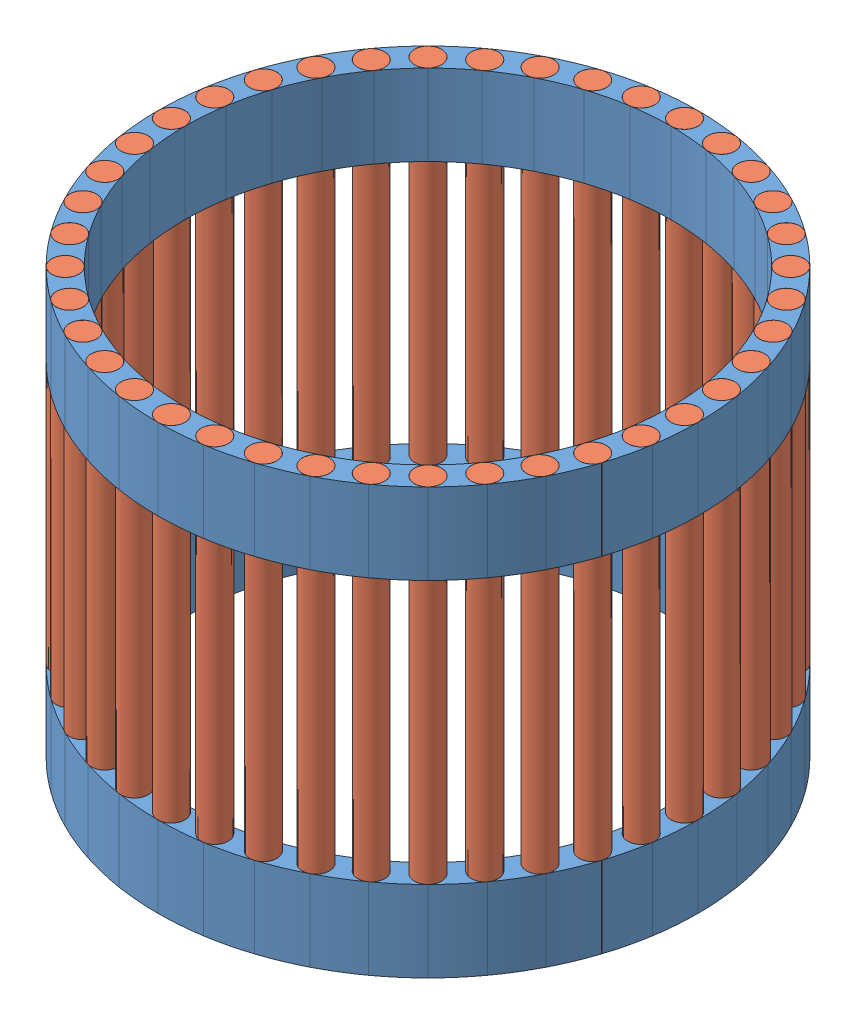
SolidWorks assembly Free Design Assembly, configuration Default. Lengths in mm.
Overall size (290.61 200.03 290.61).
42 component instances, 2 part files, 87 mates.
Components (placement in the parent):
- Free Design-1: Free Design [Default] at origin size (254 38.1 254)
- SchweykZeyn Light Sculpture Rods-1: SchweykZeyn Light Sculpture Rods [7.875 inch] at (-85.3124 0 85.3124) size (12.7 200.03 12.7)
- SchweykZeyn Light Sculpture Rods-15: SchweykZeyn Light Sculpture Rods [7.875 inch] at (-70.9163 0 97.6079) x (0.982082 0 -0.188455) z (0.188455 0 0.982082) size (12.7 200.03 12.7)
- SchweykZeyn Light Sculpture Rods-16: SchweykZeyn Light Sculpture Rods [7.875 inch] at (-54.774 0 107.4999) x (0.918365 0 -0.395734) z (0.395734 0 0.918365) size (12.7 200.03 12.7)
- SchweykZeyn Light Sculpture Rods-17: SchweykZeyn Light Sculpture Rods [7.875 inch] at (-37.2829 0 114.745) x (0.8 0 -0.6) z (0.6 0 0.8) size (12.7 200.03 12.7)
- SchweykZeyn Light Sculpture Rods-18: SchweykZeyn Light Sculpture Rods [7.875 inch] at (-18.8738 0 119.1646) x (0.63358 0 -0.773678) z (0.773678 0 0.63358) size (12.7 200.03 12.7)
- SchweykZeyn Light Sculpture Rods-19: SchweykZeyn Light Sculpture Rods [7.875 inch] at (0 0 120.65) x (0.443629 0 -0.896211) z (0.896211 0 0.443629) size (12.7 200.03 12.7)
- SchweykZeyn Light Sculpture Rods-20: SchweykZeyn Light Sculpture Rods [7.875 inch] at (18.8738 0 119.1646) x (0.263225 0 -0.964735) z (0.964735 0 0.263225) size (12.7 200.03 12.7)
- SchweykZeyn Light Sculpture Rods-21: SchweykZeyn Light Sculpture Rods [7.875 inch] at (37.2829 0 114.745) x (0.120178 0 -0.992752) z (0.992752 0 0.120178) size (12.7 200.03 12.7)
- SchweykZeyn Light Sculpture Rods-23: SchweykZeyn Light Sculpture Rods [7.875 inch] at (-107.4999 0 54.774) x (0 0 -1) z (1 0 0) size (12.7 200.03 12.7)
- SchweykZeyn Light Sculpture Rods-24: SchweykZeyn Light Sculpture Rods [7.875 inch] at (-114.745 0 37.2829) x (0.030377 0 -0.999538) z (0.999538 0 0.030377) size (12.7 200.03 12.7)
- SchweykZeyn Light Sculpture Rods-25: SchweykZeyn Light Sculpture Rods [7.875 inch] at (-119.1646 0 18.8738) x (0.120178 0 -0.992752) z (0.992752 0 0.120178) size (12.7 200.03 12.7)
- SchweykZeyn Light Sculpture Rods-26: SchweykZeyn Light Sculpture Rods [7.875 inch] at (-120.65 0 0) x (0.263225 0 -0.964735) z (0.964735 0 0.263225) size (12.7 200.03 12.7)
- SchweykZeyn Light Sculpture Rods-27: SchweykZeyn Light Sculpture Rods [7.875 inch] at (-119.1646 0 -18.8738) x (0.443629 0 -0.896211) z (0.896211 0 0.443629) size (12.7 200.03 12.7)
- SchweykZeyn Light Sculpture Rods-28: SchweykZeyn Light Sculpture Rods [7.875 inch] at (-114.745 0 -37.2829) x (0.63358 0 -0.773678) z (0.773678 0 0.63358) size (12.7 200.03 12.7)
- SchweykZeyn Light Sculpture Rods-29: SchweykZeyn Light Sculpture Rods [7.875 inch] at (-107.4999 0 -54.774) x (0.8 0 -0.6) z (0.6 0 0.8) size (12.7 200.03 12.7)
- SchweykZeyn Light Sculpture Rods-30: SchweykZeyn Light Sculpture Rods [7.875 inch] at (-97.6079 0 -70.9163) x (0.918365 0 -0.395734) z (0.395734 0 0.918365) size (12.7 200.03 12.7)
- SchweykZeyn Light Sculpture Rods-31: SchweykZeyn Light Sculpture Rods [7.875 inch] at (-85.3124 0 -85.3124) x (0.982082 0 -0.188455) z (0.188455 0 0.982082) size (12.7 200.03 12.7)
- SchweykZeyn Light Sculpture Rods-32: SchweykZeyn Light Sculpture Rods [7.875 inch] at (-70.9163 0 -97.6079) size (12.7 200.03 12.7)
- SchweykZeyn Light Sculpture Rods-33: SchweykZeyn Light Sculpture Rods [7.875 inch] at (-54.774 0 -107.4999) x (0.987317 0 0.158763) z (-0.158763 0 0.987317) size (12.7 200.03 12.7)
- SchweykZeyn Light Sculpture Rods-34: SchweykZeyn Light Sculpture Rods [7.875 inch] at (-37.2829 0 -114.745) x (0.958237 0 0.285974) z (-0.285974 0 0.958237) size (12.7 200.03 12.7)
- SchweykZeyn Light Sculpture Rods-35: SchweykZeyn Light Sculpture Rods [7.875 inch] at (-18.8738 0 -119.1646) x (0.923077 0 0.384615) z (-0.384615 0 0.923077) size (12.7 200.03 12.7)
- SchweykZeyn Light Sculpture Rods-36: SchweykZeyn Light Sculpture Rods [7.875 inch] at (0 0 -120.65) x (0.888293 0 0.459277) z (-0.459277 0 0.888293) size (12.7 200.03 12.7)
- SchweykZeyn Light Sculpture Rods-37: SchweykZeyn Light Sculpture Rods [7.875 inch] at (18.8738 0 -119.1646) x (0.857529 0 0.514435) z (-0.514435 0 0.857529) size (12.7 200.03 12.7)
- SchweykZeyn Light Sculpture Rods-38: SchweykZeyn Light Sculpture Rods [7.875 inch] at (37.2829 0 -114.745) x (0.832666 0 0.553776) z (-0.553776 0 0.832666) size (12.7 200.03 12.7)
- SchweykZeyn Light Sculpture Rods-39: SchweykZeyn Light Sculpture Rods [7.875 inch] at (54.774 0 -107.4999) x (0.814585 0 0.580044) z (-0.580044 0 0.814585) size (12.7 200.03 12.7)
- SchweykZeyn Light Sculpture Rods-40: SchweykZeyn Light Sculpture Rods [7.875 inch] at (70.9163 0 -97.6079) x (0.803653 0 0.595098) z (-0.595098 0 0.803653) size (12.7 200.03 12.7)
- SchweykZeyn Light Sculpture Rods-41: SchweykZeyn Light Sculpture Rods [7.875 inch] at (85.3124 0 -85.3124) x (-0.546944 0 0.837169) z (-0.837169 0 -0.546944) size (12.7 200.03 12.7)
- SchweykZeyn Light Sculpture Rods-42: SchweykZeyn Light Sculpture Rods [7.875 inch] at (97.6079 0 -70.9163) x (0.803653 0 0.595098) z (-0.595098 0 0.803653) size (12.7 200.03 12.7)
- SchweykZeyn Light Sculpture Rods-43: SchweykZeyn Light Sculpture Rods [7.875 inch] at (107.4999 0 -54.774) x (0.814585 0 0.580044) z (-0.580044 0 0.814585) size (12.7 200.03 12.7)
- SchweykZeyn Light Sculpture Rods-44: SchweykZeyn Light Sculpture Rods [7.875 inch] at (114.745 0 -37.2829) x (0.832666 0 0.553776) z (-0.553776 0 0.832666) size (12.7 200.03 12.7)
- SchweykZeyn Light Sculpture Rods-45: SchweykZeyn Light Sculpture Rods [7.875 inch] at (119.1646 0 -18.8738) x (0.857529 0 0.514435) z (-0.514435 0 0.857529) size (12.7 200.03 12.7)
- SchweykZeyn Light Sculpture Rods-46: SchweykZeyn Light Sculpture Rods [7.875 inch] at (120.65 0 0) x (0.888293 0 0.459277) z (-0.459277 0 0.888293) size (12.7 200.03 12.7)
- SchweykZeyn Light Sculpture Rods-47: SchweykZeyn Light Sculpture Rods [7.875 inch] at (119.1646 0 18.8738) x (0.923077 0 0.384615) z (-0.384615 0 0.923077) size (12.7 200.03 12.7)
- SchweykZeyn Light Sculpture Rods-48: SchweykZeyn Light Sculpture Rods [7.875 inch] at (114.745 0 37.2829) x (0.958237 0 0.285974) z (-0.285974 0 0.958237) size (12.7 200.03 12.7)
- SchweykZeyn Light Sculpture Rods-49: SchweykZeyn Light Sculpture Rods [7.875 inch] at (107.4999 0 54.774) x (0.987317 0 0.158763) z (-0.158763 0 0.987317) size (12.7 200.03 12.7)
- SchweykZeyn Light Sculpture Rods-50: SchweykZeyn Light Sculpture Rods [7.875 inch] at (97.6079 0 70.9163) size (12.7 200.03 12.7)
- SchweykZeyn Light Sculpture Rods-51: SchweykZeyn Light Sculpture Rods [7.875 inch] at (85.3124 0 85.3124) x (0.982082 0 -0.188455) z (0.188455 0 0.982082) size (12.7 200.03 12.7)
- SchweykZeyn Light Sculpture Rods-52: SchweykZeyn Light Sculpture Rods [7.875 inch] at (70.9163 0 97.6079) x (0.918365 0 -0.395734) z (0.395734 0 0.918365) size (12.7 200.03 12.7)
- SchweykZeyn Light Sculpture Rods-53: SchweykZeyn Light Sculpture Rods [7.875 inch] at (54.774 0 107.4999) x (0.8 0 -0.6) z (0.6 0 0.8) size (12.7 200.03 12.7)
- SchweykZeyn Light Sculpture Rods-60: SchweykZeyn Light Sculpture Rods [7.875 inch] at (-97.6079 0 70.9163) x (0.982082 0 -0.188455) z (0.188455 0 0.982082) size (12.7 200.03 12.7)
- Free Design-2: Free Design [Default] at (0 161.925 0) x (-0.987688 0 0.156434) z (-0.156434 0 -0.987688) size (254 38.1 254)
Mates (geometry in assembly coordinates):
- Coincident16: coincident aligned: plane of Free Design-1 through (0 0 0) normal (0 -1 0); plane of SchweykZeyn Light Sculpture Rods-1 through (-85.3124 0 85.3124) normal (0 -1 0)
- Concentric5: concentric aligned: cylinder of SchweykZeyn Light Sculpture Rods-1 through (-85.3124 200.025 85.3124) axis (0 -1 0) radius 6.35; cylinder of Free Design-1 through (-85.3124 38.1 85.3124) axis (0 -1 0) radius 6.35
- Concentric6: concentric aligned: cylinder of SchweykZeyn Light Sculpture Rods-1 through (-85.3124 200.025 85.3124) axis (0 -1 0) radius 6.35; cylinder of Free Design-1 through (-85.3124 38.1 85.3124) axis (0 -1 0) radius 6.35
- Coincident17: coincident aligned: plane of Free Design-1 through (0 0 0) normal (0 -1 0); plane of SchweykZeyn Light Sculpture Rods-15 through (-70.9163 0 97.6079) normal (0 -1 0)
- Concentric7: concentric aligned: cylinder of Free Design-1 through (-70.9163 38.1 97.6079) axis (0 -1 0) radius 6.35; cylinder of SchweykZeyn Light Sculpture Rods-15 through (-70.9163 200.025 97.6079) axis (0 -1 0) radius 6.35
- Coincident18: coincident aligned: plane of Free Design-1 through (0 0 0) normal (0 -1 0); plane of SchweykZeyn Light Sculpture Rods-16 through (-54.774 0 107.4999) normal (0 -1 0)
- Concentric8: concentric aligned: cylinder of Free Design-1 through (-54.774 38.1 107.4999) axis (0 -1 0) radius 6.35; cylinder of SchweykZeyn Light Sculpture Rods-16 through (-54.774 200.025 107.4999) axis (0 -1 0) radius 6.35
- Coincident19: coincident aligned: plane of Free Design-1 through (0 0 0) normal (0 -1 0); plane of SchweykZeyn Light Sculpture Rods-17 through (-37.2829 0 114.745) normal (0 -1 0)
- Concentric9: concentric aligned: cylinder of Free Design-1 through (-37.2829 38.1 114.745) axis (0 -1 0) radius 6.35; cylinder of SchweykZeyn Light Sculpture Rods-17 through (-37.2829 200.025 114.745) axis (0 -1 0) radius 6.35
- Coincident20: coincident aligned: plane of Free Design-1 through (0 0 0) normal (0 -1 0); plane of SchweykZeyn Light Sculpture Rods-18 through (-18.8738 0 119.1646) normal (0 -1 0)
- Concentric10: concentric aligned: cylinder of Free Design-1 through (-18.8738 38.1 119.1646) axis (0 -1 0) radius 6.35; cylinder of SchweykZeyn Light Sculpture Rods-18 through (-18.8738 200.025 119.1646) axis (0 -1 0) radius 6.35
- Coincident21: coincident aligned: plane of Free Design-1 through (0 0 0) normal (0 -1 0); plane of SchweykZeyn Light Sculpture Rods-19 through (0 0 120.65) normal (0 -1 0)
- Concentric11: concentric aligned: cylinder of Free Design-1 through (0 38.1 120.65) axis (0 -1 0) radius 6.35; cylinder of SchweykZeyn Light Sculpture Rods-19 through (0 200.025 120.65) axis (0 -1 0) radius 6.35
- Coincident22: coincident aligned: plane of Free Design-1 through (0 0 0) normal (0 -1 0); plane of SchweykZeyn Light Sculpture Rods-20 through (18.8738 0 119.1646) normal (0 -1 0)
- Concentric12: concentric aligned: cylinder of Free Design-1 through (18.8738 38.1 119.1646) axis (0 -1 0) radius 6.35; cylinder of SchweykZeyn Light Sculpture Rods-20 through (18.8738 200.025 119.1646) axis (0 -1 0) radius 6.35
- Coincident23: coincident aligned: plane of Free Design-1 through (0 0 0) normal (0 -1 0); plane of SchweykZeyn Light Sculpture Rods-21 through (37.2829 0 114.745) normal (0 -1 0)
- Concentric13: concentric aligned: cylinder of Free Design-1 through (37.2829 38.1 114.745) axis (0 -1 0) radius 6.35; cylinder of SchweykZeyn Light Sculpture Rods-21 through (37.2829 200.025 114.745) axis (0 -1 0) radius 6.35
- Coincident25: coincident aligned: plane of Free Design-1 through (0 0 0) normal (0 -1 0); plane of SchweykZeyn Light Sculpture Rods-23 through (-107.4999 0 54.774) normal (0 -1 0)
- Concentric15: concentric aligned: cylinder of Free Design-1 through (-107.4999 38.1 54.774) axis (0 -1 0) radius 6.35; cylinder of SchweykZeyn Light Sculpture Rods-23 through (-107.4999 200.025 54.774) axis (0 -1 0) radius 6.35
- Coincident26: coincident aligned: plane of Free Design-1 through (0 0 0) normal (0 -1 0); plane of SchweykZeyn Light Sculpture Rods-24 through (-114.745 0 37.2829) normal (0 -1 0)
- Concentric16: concentric aligned: cylinder of Free Design-1 through (-114.745 38.1 37.2829) axis (0 -1 0) radius 6.35; cylinder of SchweykZeyn Light Sculpture Rods-24 through (-114.745 200.025 37.2829) axis (0 -1 0) radius 6.35
- Coincident27: coincident aligned: plane of Free Design-1 through (0 0 0) normal (0 -1 0); plane of SchweykZeyn Light Sculpture Rods-25 through (-119.1646 0 18.8738) normal (0 -1 0)
- Concentric17: concentric aligned: cylinder of Free Design-1 through (-119.1646 38.1 18.8738) axis (0 -1 0) radius 6.35; cylinder of SchweykZeyn Light Sculpture Rods-25 through (-119.1646 200.025 18.8738) axis (0 -1 0) radius 6.35
- Coincident28: coincident aligned: plane of Free Design-1 through (0 0 0) normal (0 -1 0); plane of SchweykZeyn Light Sculpture Rods-26 through (-120.65 0 0) normal (0 -1 0)
- Concentric18: concentric aligned: cylinder of Free Design-1 through (-120.65 38.1 0) axis (0 -1 0) radius 6.35; cylinder of SchweykZeyn Light Sculpture Rods-26 through (-120.65 200.025 0) axis (0 -1 0) radius 6.35
- Coincident29: coincident aligned: plane of Free Design-1 through (0 0 0) normal (0 -1 0); plane of SchweykZeyn Light Sculpture Rods-27 through (-119.1646 0 -18.8738) normal (0 -1 0)
- Concentric19: concentric aligned: cylinder of Free Design-1 through (-119.1646 38.1 -18.8738) axis (0 -1 0) radius 6.35; cylinder of SchweykZeyn Light Sculpture Rods-27 through (-119.1646 200.025 -18.8738) axis (0 -1 0) radius 6.35
- Coincident30: coincident aligned: plane of Free Design-1 through (0 0 0) normal (0 -1 0); plane of SchweykZeyn Light Sculpture Rods-28 through (-114.745 0 -37.2829) normal (0 -1 0)
- Concentric20: concentric aligned: cylinder of Free Design-1 through (-114.745 38.1 -37.2829) axis (0 -1 0) radius 6.35; cylinder of SchweykZeyn Light Sculpture Rods-28 through (-114.745 200.025 -37.2829) axis (0 -1 0) radius 6.35
- Coincident31: coincident aligned: plane of Free Design-1 through (0 0 0) normal (0 -1 0); plane of SchweykZeyn Light Sculpture Rods-29 through (-107.4999 0 -54.774) normal (0 -1 0)
- Concentric21: concentric aligned: cylinder of Free Design-1 through (-107.4999 38.1 -54.774) axis (0 -1 0) radius 6.35; cylinder of SchweykZeyn Light Sculpture Rods-29 through (-107.4999 200.025 -54.774) axis (0 -1 0) radius 6.35
- Coincident32: coincident aligned: plane of Free Design-1 through (0 0 0) normal (0 -1 0); plane of SchweykZeyn Light Sculpture Rods-30 through (-97.6079 0 -70.9163) normal (0 -1 0)
- Concentric22: concentric aligned: cylinder of Free Design-1 through (-97.6079 38.1 -70.9163) axis (0 -1 0) radius 6.35; cylinder of SchweykZeyn Light Sculpture Rods-30 through (-97.6079 200.025 -70.9163) axis (0 -1 0) radius 6.35
- Coincident33: coincident aligned: plane of Free Design-1 through (0 0 0) normal (0 -1 0); plane of SchweykZeyn Light Sculpture Rods-31 through (-85.3124 0 -85.3124) normal (0 -1 0)
- Concentric23: concentric aligned: cylinder of Free Design-1 through (-85.3124 38.1 -85.3124) axis (0 -1 0) radius 6.35; cylinder of SchweykZeyn Light Sculpture Rods-31 through (-85.3124 200.025 -85.3124) axis (0 -1 0) radius 6.35
- Coincident34: coincident aligned: plane of Free Design-1 through (0 0 0) normal (0 -1 0); plane of SchweykZeyn Light Sculpture Rods-32 through (-70.9163 0 -97.6079) normal (0 -1 0)
- Concentric24: concentric aligned: cylinder of Free Design-1 through (-70.9163 38.1 -97.6079) axis (0 -1 0) radius 6.35; cylinder of SchweykZeyn Light Sculpture Rods-32 through (-70.9163 200.025 -97.6079) axis (0 -1 0) radius 6.35
- Coincident35: coincident aligned: plane of Free Design-1 through (0 0 0) normal (0 -1 0); plane of SchweykZeyn Light Sculpture Rods-33 through (-54.774 0 -107.4999) normal (0 -1 0)
- Concentric25: concentric aligned: cylinder of Free Design-1 through (-54.774 38.1 -107.4999) axis (0 -1 0) radius 6.35; cylinder of SchweykZeyn Light Sculpture Rods-33 through (-54.774 200.025 -107.4999) axis (0 -1 0) radius 6.35
- Coincident36: coincident aligned: plane of Free Design-1 through (0 0 0) normal (0 -1 0); plane of SchweykZeyn Light Sculpture Rods-34 through (-37.2829 0 -114.745) normal (0 -1 0)
- Concentric26: concentric aligned: cylinder of Free Design-1 through (-37.2829 38.1 -114.745) axis (0 -1 0) radius 6.35; cylinder of SchweykZeyn Light Sculpture Rods-34 through (-37.2829 200.025 -114.745) axis (0 -1 0) radius 6.35
- Coincident37: coincident aligned: plane of Free Design-1 through (0 0 0) normal (0 -1 0); plane of SchweykZeyn Light Sculpture Rods-35 through (-18.8738 0 -119.1646) normal (0 -1 0)
- Concentric27: concentric aligned: cylinder of Free Design-1 through (-18.8738 38.1 -119.1646) axis (0 -1 0) radius 6.35; cylinder of SchweykZeyn Light Sculpture Rods-35 through (-18.8738 200.025 -119.1646) axis (0 -1 0) radius 6.35
- Coincident38: coincident aligned: plane of Free Design-1 through (0 0 0) normal (0 -1 0); plane of SchweykZeyn Light Sculpture Rods-36 through (0 0 -120.65) normal (0 -1 0)
- Concentric28: concentric aligned: cylinder of Free Design-1 through (0 38.1 -120.65) axis (0 -1 0) radius 6.35; cylinder of SchweykZeyn Light Sculpture Rods-36 through (0 200.025 -120.65) axis (0 -1 0) radius 6.35
- Coincident39: coincident aligned: plane of Free Design-1 through (0 0 0) normal (0 -1 0); plane of SchweykZeyn Light Sculpture Rods-37 through (18.8738 0 -119.1646) normal (0 -1 0)
- Concentric29: concentric aligned: cylinder of Free Design-1 through (18.8738 38.1 -119.1646) axis (0 -1 0) radius 6.35; cylinder of SchweykZeyn Light Sculpture Rods-37 through (18.8738 200.025 -119.1646) axis (0 -1 0) radius 6.35
- Coincident40: coincident aligned: plane of Free Design-1 through (0 0 0) normal (0 -1 0); plane of SchweykZeyn Light Sculpture Rods-38 through (37.2829 0 -114.745) normal (0 -1 0)
- Concentric30: concentric aligned: cylinder of Free Design-1 through (37.2829 38.1 -114.745) axis (0 -1 0) radius 6.35; cylinder of SchweykZeyn Light Sculpture Rods-38 through (37.2829 200.025 -114.745) axis (0 -1 0) radius 6.35
- Coincident41: coincident aligned: plane of Free Design-1 through (0 0 0) normal (0 -1 0); plane of SchweykZeyn Light Sculpture Rods-39 through (54.774 0 -107.4999) normal (0 -1 0)
- Concentric31: concentric aligned: cylinder of Free Design-1 through (54.774 38.1 -107.4999) axis (0 -1 0) radius 6.35; cylinder of SchweykZeyn Light Sculpture Rods-39 through (54.774 200.025 -107.4999) axis (0 -1 0) radius 6.35
- Coincident42: coincident aligned: plane of Free Design-1 through (0 0 0) normal (0 -1 0); plane of SchweykZeyn Light Sculpture Rods-40 through (70.9163 0 -97.6079) normal (0 -1 0)
- Concentric32: concentric aligned: cylinder of Free Design-1 through (70.9163 38.1 -97.6079) axis (0 -1 0) radius 6.35; cylinder of SchweykZeyn Light Sculpture Rods-40 through (70.9163 200.025 -97.6079) axis (0 -1 0) radius 6.35
- Coincident43: coincident aligned: plane of Free Design-1 through (0 0 0) normal (0 -1 0); plane of SchweykZeyn Light Sculpture Rods-41 through (85.3124 0 -85.3124) normal (0 -1 0)
- Concentric33: concentric aligned: cylinder of Free Design-1 through (85.3124 38.1 -85.3124) axis (0 -1 0) radius 6.35; cylinder of SchweykZeyn Light Sculpture Rods-41 through (85.3124 200.025 -85.3124) axis (0 -1 0) radius 6.35
- Coincident44: coincident aligned: plane of Free Design-1 through (0 0 0) normal (0 -1 0); plane of SchweykZeyn Light Sculpture Rods-42 through (97.6079 0 -70.9163) normal (0 -1 0)
- Concentric34: concentric aligned: cylinder of Free Design-1 through (97.6079 38.1 -70.9163) axis (0 -1 0) radius 6.35; cylinder of SchweykZeyn Light Sculpture Rods-42 through (97.6079 200.025 -70.9163) axis (0 -1 0) radius 6.35
- Coincident45: coincident aligned: plane of Free Design-1 through (0 0 0) normal (0 -1 0); plane of SchweykZeyn Light Sculpture Rods-43 through (107.4999 0 -54.774) normal (0 -1 0)
- Concentric35: concentric aligned: cylinder of Free Design-1 through (107.4999 38.1 -54.774) axis (0 -1 0) radius 6.35; cylinder of SchweykZeyn Light Sculpture Rods-43 through (107.4999 200.025 -54.774) axis (0 -1 0) radius 6.35
- Coincident46: coincident aligned: plane of Free Design-1 through (0 0 0) normal (0 -1 0); plane of SchweykZeyn Light Sculpture Rods-44 through (114.745 0 -37.2829) normal (0 -1 0)
- Concentric36: concentric aligned: cylinder of Free Design-1 through (114.745 38.1 -37.2829) axis (0 -1 0) radius 6.35; cylinder of SchweykZeyn Light Sculpture Rods-44 through (114.745 200.025 -37.2829) axis (0 -1 0) radius 6.35
- Coincident47: coincident aligned: plane of Free Design-1 through (0 0 0) normal (0 -1 0); plane of SchweykZeyn Light Sculpture Rods-45 through (119.1646 0 -18.8738) normal (0 -1 0)
- Concentric37: concentric aligned: cylinder of Free Design-1 through (119.1646 38.1 -18.8738) axis (0 -1 0) radius 6.35; cylinder of SchweykZeyn Light Sculpture Rods-45 through (119.1646 200.025 -18.8738) axis (0 -1 0) radius 6.35
- Coincident48: coincident aligned: plane of Free Design-1 through (0 0 0) normal (0 -1 0); plane of SchweykZeyn Light Sculpture Rods-46 through (120.65 0 0) normal (0 -1 0)
- Concentric38: concentric aligned: cylinder of Free Design-1 through (120.65 38.1 0) axis (0 -1 0) radius 6.35; cylinder of SchweykZeyn Light Sculpture Rods-46 through (120.65 200.025 0) axis (0 -1 0) radius 6.35
- Coincident49: coincident aligned: plane of Free Design-1 through (0 0 0) normal (0 -1 0); plane of SchweykZeyn Light Sculpture Rods-47 through (119.1646 0 18.8738) normal (0 -1 0)
- Concentric39: concentric aligned: cylinder of Free Design-1 through (119.1646 38.1 18.8738) axis (0 -1 0) radius 6.35; cylinder of SchweykZeyn Light Sculpture Rods-47 through (119.1646 200.025 18.8738) axis (0 -1 0) radius 6.35
- Coincident50: coincident aligned: plane of Free Design-1 through (0 0 0) normal (0 -1 0); plane of SchweykZeyn Light Sculpture Rods-48 through (114.745 0 37.2829) normal (0 -1 0)
- Concentric40: concentric aligned: cylinder of Free Design-1 through (114.745 38.1 37.2829) axis (0 -1 0) radius 6.35; cylinder of SchweykZeyn Light Sculpture Rods-48 through (114.745 200.025 37.2829) axis (0 -1 0) radius 6.35
- Coincident51: coincident aligned: plane of Free Design-1 through (0 0 0) normal (0 -1 0); plane of SchweykZeyn Light Sculpture Rods-49 through (107.4999 0 54.774) normal (0 -1 0)
- Concentric41: concentric aligned: cylinder of Free Design-1 through (107.4999 38.1 54.774) axis (0 -1 0) radius 6.35; cylinder of SchweykZeyn Light Sculpture Rods-49 through (107.4999 200.025 54.774) axis (0 -1 0) radius 6.35
- Coincident52: coincident aligned: plane of Free Design-1 through (0 0 0) normal (0 -1 0); plane of SchweykZeyn Light Sculpture Rods-50 through (97.6079 0 70.9163) normal (0 -1 0)
- Concentric42: concentric aligned: cylinder of Free Design-1 through (97.6079 38.1 70.9163) axis (0 -1 0) radius 6.35; cylinder of SchweykZeyn Light Sculpture Rods-50 through (97.6079 200.025 70.9163) axis (0 -1 0) radius 6.35
- Coincident53: coincident aligned: plane of Free Design-1 through (0 0 0) normal (0 -1 0); plane of SchweykZeyn Light Sculpture Rods-51 through (85.3124 0 85.3124) normal (0 -1 0)
- Concentric43: concentric aligned: cylinder of Free Design-1 through (85.3124 38.1 85.3124) axis (0 -1 0) radius 6.35; cylinder of SchweykZeyn Light Sculpture Rods-51 through (85.3124 200.025 85.3124) axis (0 -1 0) radius 6.35
- Coincident54: coincident aligned: plane of Free Design-1 through (0 0 0) normal (0 -1 0); plane of SchweykZeyn Light Sculpture Rods-52 through (70.9163 0 97.6079) normal (0 -1 0)
- Concentric44: concentric aligned: cylinder of Free Design-1 through (70.9163 38.1 97.6079) axis (0 -1 0) radius 6.35; cylinder of SchweykZeyn Light Sculpture Rods-52 through (70.9163 200.025 97.6079) axis (0 -1 0) radius 6.35
- Coincident55: coincident aligned: plane of Free Design-1 through (0 0 0) normal (0 -1 0); plane of SchweykZeyn Light Sculpture Rods-53 through (54.774 0 107.4999) normal (0 -1 0)
- Concentric45: concentric aligned: cylinder of Free Design-1 through (54.774 38.1 107.4999) axis (0 -1 0) radius 6.35; cylinder of SchweykZeyn Light Sculpture Rods-53 through (54.774 200.025 107.4999) axis (0 -1 0) radius 6.35
- Coincident63: coincident aligned: plane of Free Design-1 through (0 0 0) normal (0 -1 0); plane of SchweykZeyn Light Sculpture Rods-60 through (-97.6079 0 70.9163) normal (0 -1 0)
- Concentric47: concentric aligned: cylinder of Free Design-1 through (-97.6079 38.1 70.9163) axis (0 -1 0) radius 6.35; cylinder of SchweykZeyn Light Sculpture Rods-60 through (-97.6079 200.025 70.9163) axis (0 -1 0) radius 6.35
- Coincident65: coincident aligned: plane of SchweykZeyn Light Sculpture Rods-43 through (107.4999 200.025 -54.774) normal (0 1 0); plane of Free Design-2 through (5.6432 200.025 2.6935) normal (0 1 0)
- Coincident66: coincident aligned: plane of SchweykZeyn Light Sculpture Rods-52 through (70.9163 200.025 97.6079) normal (0 1 0); plane of Free Design-2 through (5.6432 200.025 2.6935) normal (0 1 0)
- Coincident67: coincident aligned: plane of SchweykZeyn Light Sculpture Rods-21 through (37.2829 200.025 114.745) normal (0 1 0); plane of Free Design-2 through (5.6432 200.025 2.6935) normal (0 1 0)
- Coincident68: coincident aligned: plane of SchweykZeyn Light Sculpture Rods-39 through (54.774 200.025 -107.4999) normal (0 1 0); plane of Free Design-2 through (5.6432 200.025 2.6935) normal (0 1 0)
- Concentric50: concentric aligned: cylinder of SchweykZeyn Light Sculpture Rods-39 through (54.774 200.025 -107.4999) axis (0 -1 0) radius 6.35; cylinder of Free Design-2 through (54.774 200.025 -107.4999) axis (0 -1 0) radius 6.35
- Concentric51: concentric aligned: cylinder of SchweykZeyn Light Sculpture Rods-18 through (-18.8738 200.025 119.1646) axis (0 -1 0) radius 6.35; cylinder of Free Design-2 through (-18.8738 200.025 119.1646) axis (0 -1 0) radius 6.35
